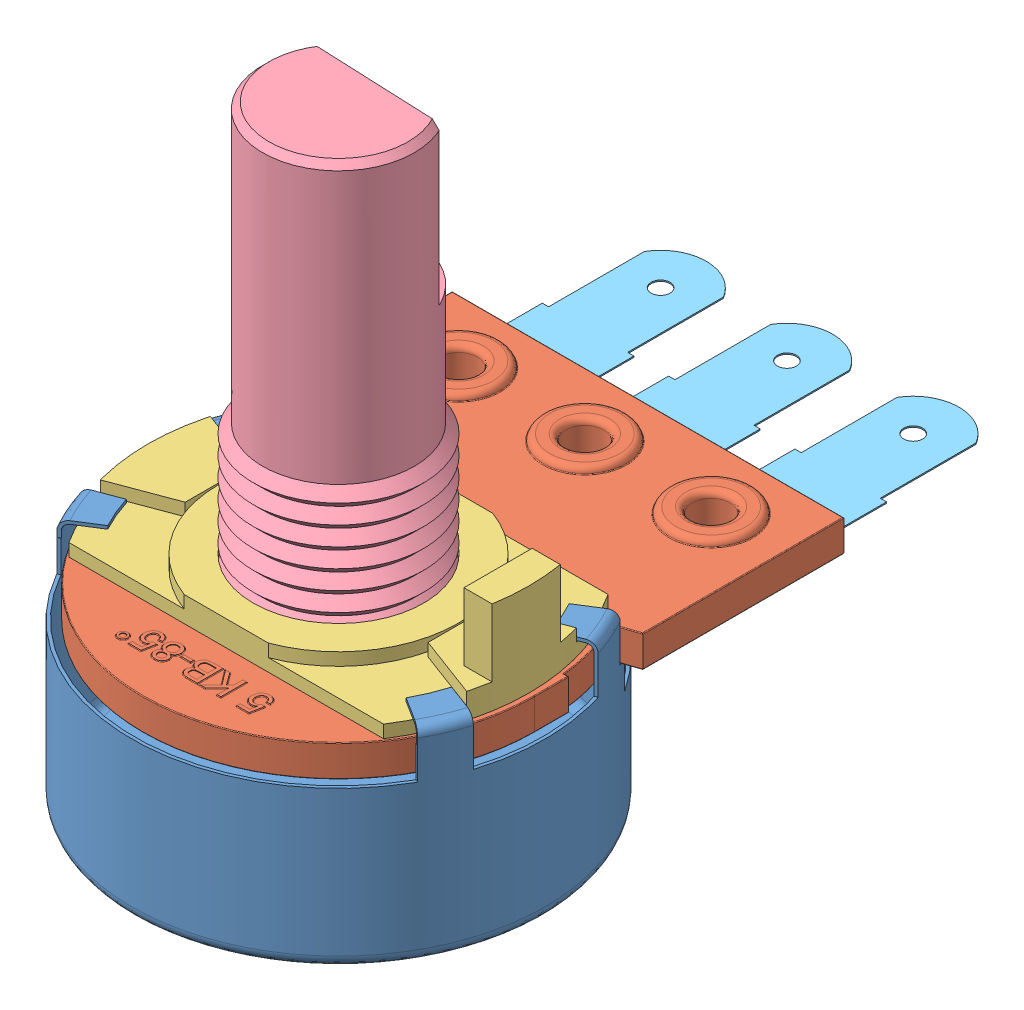
SolidWorks assembly User Library-Potentiometer-4, configuration -1. Lengths in mm.
Overall size (16.64 24.38 28.19).
5 component instances, 5 part files, 13 mates.
Components (placement in the parent):
- User Library-Potentiometer-4_Pot Base-1: User Library-Potentiometer-4_Pot Base [-1] at origin size (16.64 8.26 16.64)
- User Library-Potentiometer-4_POT Board-1: User Library-Potentiometer-4_POT Board [-1] at (0 6.35 0) x (0 0 -1) z (1 0 0) size (20.32 1.53 15.75)
- User Library-Potentiometer-4_POT PLATE 1-1: User Library-Potentiometer-4_POT PLATE 1 [Default] at (0 7.62 0) x (0 0 -1) z (0 1 0) size (9.03 15.32 3.73)
- User Library-Potentiometer-4_POT shaft-1: User Library-Potentiometer-4_POT shaft [Default] at (0 6.35 0) x (-0.042361 0 0.999102) z (0 -1 0) size (14.96 14.96 18.29)
- User Library-Potentiometer-4_POT wire connections-1: User Library-Potentiometer-4_POT wire connections [Default] at (0 6.35 0) x (0 0 1) z (0 -1 0) size (11.81 13.84 0.05)
Mates (geometry in assembly coordinates):
- Concentric1: concentric aligned: cylinder of Pot Base-1 through (0 6.35 0) axis (0 -1 0) radius 8.1915; cylinder of POT Board-1 through (0 7.62 0) axis (0 -1 0) radius 7.874
- Parallel1: parallel anti-aligned: plane of POT Board-1 through (-7.874 7.62 -12.446) normal (0 0 -1)
- Coincident2: coincident anti-aligned: plane of Pot Base-1 through (0 6.35 0) normal (0 1 0); plane of POT Board-1 through (0.5659 6.35 -0.7385) normal (0 -1 0)
- InPlace1: in place: plane of User Library-Potentiometer-4_POT Board-1 through (0.5659 7.62 -0.7385) normal (0 1 0); plane of ? through (0 7.62 0) normal (0 1 0); moOrthogonalPlaneRef_w of User Library-Potentiometer-4_POT Board-1 through (0.5659 7.62 -0.7385) normal (0 1 0); plane of ? through (0 7.62 0) normal (0 0 -1); plane of User Library-Potentiometer-4_POT Board-1 through (0.5659 7.62 -0.7385) normal (0 1 0); line of ? through (-55 0 7.62) axis (0 1 0); plane of User Library-Potentiometer-4_POT Board-1 through (0.5659 7.62 -0.7385) normal (0 1 0); unknown of User Library-Potentiometer-4_POT PLATE 1-1
- Coincident3: coincident aligned: plane of assembly through (0.5659 7.62 -0.7385) normal (0 1 0); plane of assembly through (0 7.62 0) normal (0 1 0)
- Coincident4: coincident aligned: moOrthogonalPlaneRef_w of POT Board-1 through (0 7.62 0) normal (-1 0 0); plane of POT PLATE 1-1 through (0 7.62 0) normal (-1 0 0)
- Coincident5: coincident anti-aligned: moOrthogonalPlaneRef_w of POT Board-1 through (0 7.62 0) normal (0 0 1); plane of POT PLATE 1-1 through (0 7.62 0) normal (0 0 -1)
- InPlace3: in place: plane of User Library-Potentiometer-4_POT Board-1 through (0.5659 6.35 -0.7385) normal (0 -1 0); plane of ? through (0 6.35 0) normal (0 -1 0); plane of User Library-Potentiometer-4_POT Board-1 through (0.5659 6.35 -0.7385) normal (0 -1 0); unknown of ?; plane of User Library-Potentiometer-4_POT Board-1 through (0.5659 6.35 -0.7385) normal (0 -1 0); line of ? through (-55 0 6.35) axis (0 -1 0); plane of User Library-Potentiometer-4_POT Board-1 through (0.5659 6.35 -0.7385) normal (0 -1 0); unknown of User Library-Potentiometer-4_POT wire connections-1
- Coincident9: coincident aligned: plane of ?; plane of ?
- Coincident10: coincident aligned: moOrthogonalPlaneRef_w of POT Board-1 through (0 6.35 0) normal (-1 0 0); plane of POT wire connections-1 through (0 6.35 0) normal (-1 0 0)
- Coincident11: coincident anti-aligned: moOrthogonalPlaneRef_w of POT Board-1 through (0 6.35 0) normal (0 0 -1); plane of POT wire connections-1 through (0 6.35 0) normal (0 0 1)
- Coincident12: coincident anti-aligned: plane of POT Board-1 through (0.5659 6.35 -0.7385) normal (0 -1 0); plane of POT shaft-1 through (0 6.35 0) normal (0 1 0)
- Concentric2: concentric aligned: cylinder of POT Board-1 through (0 7.62 0) axis (0 -1 0) radius 3.175; cylinder of POT shaft-1 through (0 24.384 0) axis (0 -1 0) radius 3.048
